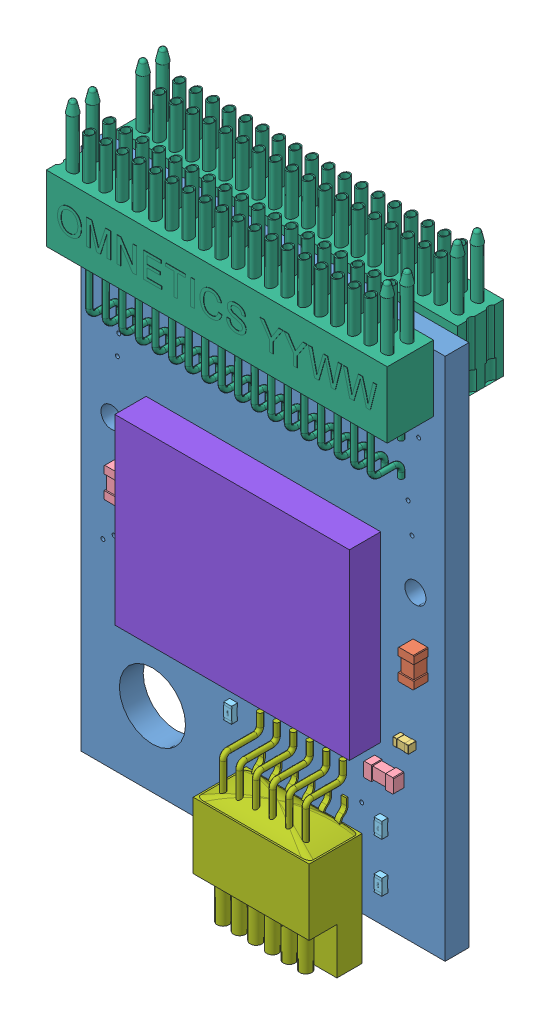
SolidWorks assembly RHD2164_headstage_bga, configuration Default. Lengths in mm.
Overall size (13.97 24.45 4.89).
12 component instances, 8 part files, 20 mates.
Components (placement in the parent):
- RHD2164_headstage_bga_PCB-1: RHD2164_headstage_bga_PCB [Default] at origin size (13.97 20.1 0.91)
- 0402c_2320560-1: 0402c_2320560 [Default] at (13.0175 9.525 0.9144) x (0 1 0) z (0 0 1) size (1.15 0.6 0.55)
- 0201c-2: 0201c [0201] at (12.5603 6.6167 1.0644) size (0.6 0.3 0.3)
- 0402r_1430758-1: 0402r_1430758 [Default] at (1.5621 9.779 0.9144) x (0 1 0) z (0 0 1) size (1.15 0.55 0.4)
- 0402r_1430758-2: 0402r_1430758 [Default] at (11.8128 5.2256 0.9144) x (-1 0 0) z (0 0 1) size (1.15 0.55 0.4)
- 0201r-3: 0201r [0201] at (5.8532 4.3049 1.0294) x (-1 0 0) z (0 1 0) size (0.3 0.23 0.6)
- 0201r-4: 0201r [0201] at (11.6205 1.4732 1.0294) x (1 0 0) z (0 -1 0) size (0.3 0.23 0.6)
- 0201r-5: 0201r [0201] at (11.6205 3.3655 1.0294) x (-1 0 0) z (0 1 0) size (0.3 0.23 0.6)
- A79025-001-1: A79025-001 [Default] at (5.715 19.1516 2.6924) size (13.15 7.44 2.12)
- A79025-001-2: A79025-001 [Default] at (8.255 19.1516 -1.778) x (-1 0 0) z (0 0 -1) size (13.15 7.44 2.12)
- A79623-001-1: A79623-001 [Default] at (8.5598 2.6543 0.9144) x (1 0 0) z (0 -1 0) size (4.45 2.05 6.53)
- RHD2164_bga-1: RHD2164_bga [Default] at (6.9977 9.5377 0.9144) size (9 7 1.2)
Mates (geometry in assembly coordinates):
- Coincident1: coincident anti-aligned: plane of rhd2164_headstage_bga-1 through (0 0 0.9144) normal (0 0 1); plane of A79623-001-1 through (8.5598 2.6543 0.9144) normal (0 0 -1)
- Parallel1: parallel aligned: plane of rhd2164_headstage_bga-1 through (13.97 0 0.9144) normal (0 -1 0); plane of A79623-001-1 through (10.7823 0.1143 2.9464) normal (0 -1 0)
- Coincident4: coincident anti-aligned: plane of rhd2164_headstage_bga-1 through (0 0 0.9144) normal (0 0 1); plane of A79025-001-1 through (13.5255 17.8816 0.9144) normal (0 0 -1)
- Coincident5: coincident anti-aligned: plane of rhd2164_headstage_bga-1 through (0 0 0) normal (0 0 -1); plane of A79025-001-2 through (0.4445 17.8816 0) normal (0 0 1)
- Distance6: distance = 0.4445 mm: line of A79025-001-1 through (13.5255 20.4216 0.9144) axis (0 -1 0); line of rhd2164_headstage_bga-1 through (13.97 0 0.9144) axis (0 1 0)
- Distance9: distance = 0.4445 mm: line of A79025-001-2 through (2.54 0.4445 20.4216) axis (0 0 -1); line of rhd2164_headstage_bga-1 through (20.1041 0 20.1041) axis (0 0 -1)
- Distance10: distance = 0.3175 mm: line of rhd2164_headstage_bga-1 through (13.97 20.1041 0.9144) axis (-1 0 0); line of A79025-001-1 through (0.4445 20.4216 0.9144) axis (1 0 0)
- Distance11: distance = 0.3175 mm: line of rhd2164_headstage_bga-1 through (13.97 13.97 20.1041) axis (0 -1 0); line of A79025-001-2 through (13.081 13.5255 20.4216) axis (0 -1 0)
- Coincident6: coincident anti-aligned: plane of rhd2164_headstage_bga-1 through (0 0 0.9144) normal (0 0 1); plane of rhd2164_bga-1 through (6.9977 9.5377 0.9144) normal (0 0 -1)
- Coincident8: coincident anti-aligned: plane of rhd2164_headstage_bga-1 through (0 0 0.9144) normal (0 0 1); plane of 0402r_1430758-1 through (0.7371 9.779 0.9144) normal (0 0 -1)
- Coincident9: coincident anti-aligned: plane of rhd2164_headstage_bga-1 through (0 0 0.9144) normal (0 0 1); plane of 0402c_2320560-1 through (12.1675 9.525 0.9144) normal (0 0 -1)
- Coincident11: coincident anti-aligned: plane of rhd2164_headstage_bga-1 through (0 0 0.9144) normal (0 0 1); plane of 0402r_1430758-2 through (11.8128 4.4006 0.9144) normal (0 0 -1)
- Coincident18: coincident anti-aligned: plane of RHD2164_headstage_bga-1 through (0 0 0.9144) normal (0 0 1); plane of 0201r-3 through (5.7032 4.6049 0.9144) normal (0 0 -1)
- Coincident19: coincident anti-aligned: plane of RHD2164_headstage_bga-1 through (0 0 0.9144) normal (0 0 1); plane of 0201r-4 through (11.7705 1.1732 0.9144) normal (0 0 -1)
- Coincident20: coincident anti-aligned: plane of RHD2164_headstage_bga-1 through (0 0 0.9144) normal (0 0 1); plane of 0201r-5 through (11.4705 3.6655 0.9144) normal (0 0 -1)
- Coincident21: coincident anti-aligned: plane of RHD2164_headstage_bga-1 through (0 0 0.9144) normal (0 0 1); plane of 0201c-2 through (12.2603 6.7667 0.9144) normal (0 0 -1)
- Parallel3: parallel aligned: plane of RHD2164_headstage_bga-1 through (13.97 0 0.9144) normal (0 -1 0); plane of 0201r-3 through (5.7032 4.0049 1.1444) normal (0 -1 0)
- Parallel4: parallel aligned: plane of RHD2164_headstage_bga-1 through (13.97 0 0.9144) normal (0 -1 0); plane of 0201r-5 through (11.4705 3.0655 1.1444) normal (0 -1 0)
- Parallel5: parallel aligned: plane of RHD2164_headstage_bga-1 through (13.97 0 0.9144) normal (0 -1 0); plane of 0201r-4 through (11.7705 1.1732 1.1444) normal (0 -1 0)
- Parallel6: parallel aligned: plane of RHD2164_headstage_bga-1 through (13.97 20.1041 0.9144) normal (1 0 0); plane of 0201c-2 through (12.8603 6.7667 0.9144) normal (1 0 0)
